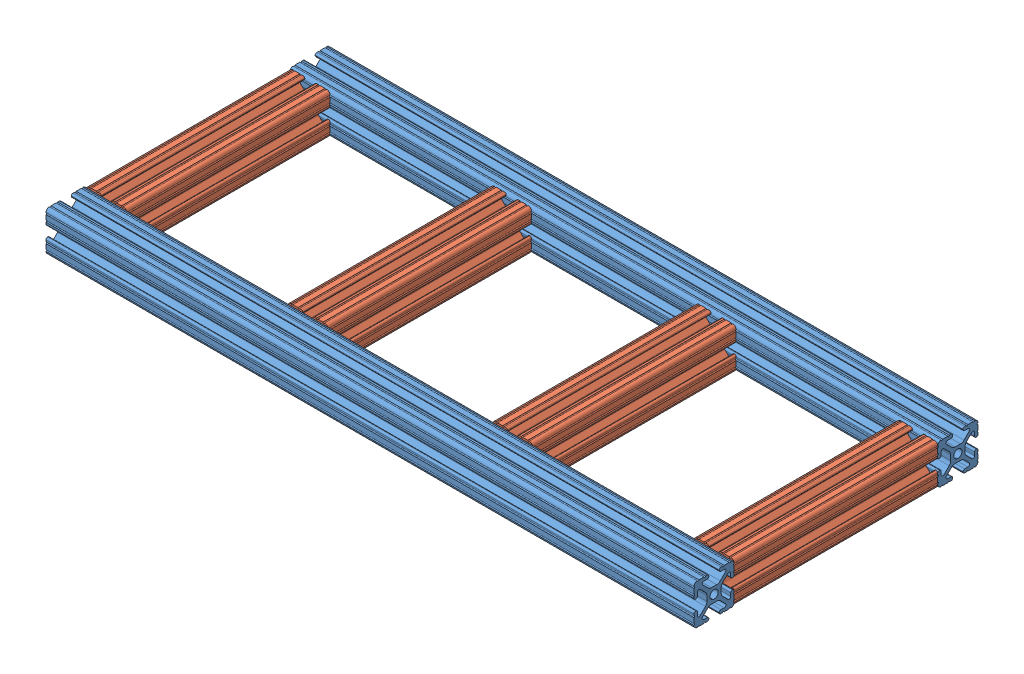
SolidWorks assembly base structure, configuration Default. Lengths in mm.
Overall size (408.43 25.4 179.07).
6 component instances, 2 part files, 17 mates.
Components (placement in the parent):
- base bar-1: base bar [Default<As Machined>] at origin size (408.43 25.4 25.4)
- base bar-2: base bar [Default<As Machined>] at (0 0 153.67) size (408.43 25.4 25.4)
- connecting bars-1: connecting bars [Default<As Machined>] at (-395.732 0 12.7) x (0 0 -1) z (0 1 0) size (128.27 25.4 25.4)
- connecting bars-2: connecting bars [Default<As Machined>] at (-139.7 0 12.7) x (0 0 -1) z (-1 0 0) size (128.27 25.4 25.4)
- connecting bars-3: connecting bars [Default<As Machined>] at (-268.732 0 12.7) x (0 0 -1) z (0 1 0) size (128.27 25.4 25.4)
- connecting bars-4: connecting bars [Default<As Machined>] at (-12.7 0 12.7) x (0 0 -1) z (0 1 0) size (128.27 25.4 25.4)
Mates (geometry in assembly coordinates):
- Coincident1: coordinate: point of base bar-1
- Coincident2: coincident anti-aligned: plane of base bar-2 through (-408.432 -6.3331 140.97) normal (0 0 -1); plane of connecting bars-4 through (-5.0292 -1.7093 140.97) normal (0 0 1)
- Coincident3: coincident: moEndPointRef_w of base bar-2; unknown of connecting bars-4
- Coincident4: coincident: unknown of base bar-2; unknown of connecting bars-4
- Coincident5: coincident: unknown of base bar-1; unknown of connecting bars-4
- Coincident6: coincident: unknown of base bar-1; unknown of connecting bars-4
- Coincident7: coincident: unknown of base bar-2; unknown of connecting bars-1
- Coincident8: coincident: unknown of base bar-1; unknown of connecting bars-1
- Coincident9: coincident: unknown of base bar-1; unknown of connecting bars-1
- Coincident10: coincident: plane of base bar-1 through (-408.432 6.3331 12.7) normal (0 0 1); plane of connecting bars-2 through (-140.4299 7.6708 12.7) normal (0 0 -1)
- Coincident11: coincident: plane of base bar-1 through (-408.432 -9.5504 12.7) normal (0 0 1); plane of connecting bars-3 through (-265.8031 -1.7093 12.7) normal (0 0 -1)
- Coincident14: coincident: line of base bar-2 through (-408.432 9.5504 140.97) axis (1 0 0); point of connecting bars-2
- Coincident15: coincident: line of base bar-1 through (-408.432 9.5504 12.7) axis (1 0 0); point of connecting bars-2
- Coincident16: coincident: line of base bar-1 through (-408.432 9.5504 12.7) axis (1 0 0); point of connecting bars-3
- Coincident17: coincident: line of base bar-2 through (-408.432 9.5504 140.97) axis (1 0 0); point of connecting bars-3
- Distance1: distance = 101.6 mm anti-aligned: plane of connecting bars-4 through (-25.4 -6.3331 140.97) normal (-1 0 0); plane of connecting bars-2 through (-127 -9.5504 140.97) normal (1 0 0)
- Distance2: distance = 101.6 mm anti-aligned: plane of connecting bars-3 through (-281.432 -6.3331 140.97) normal (-1 0 0); plane of connecting bars-1 through (-383.032 -9.5504 140.97) normal (1 0 0)
